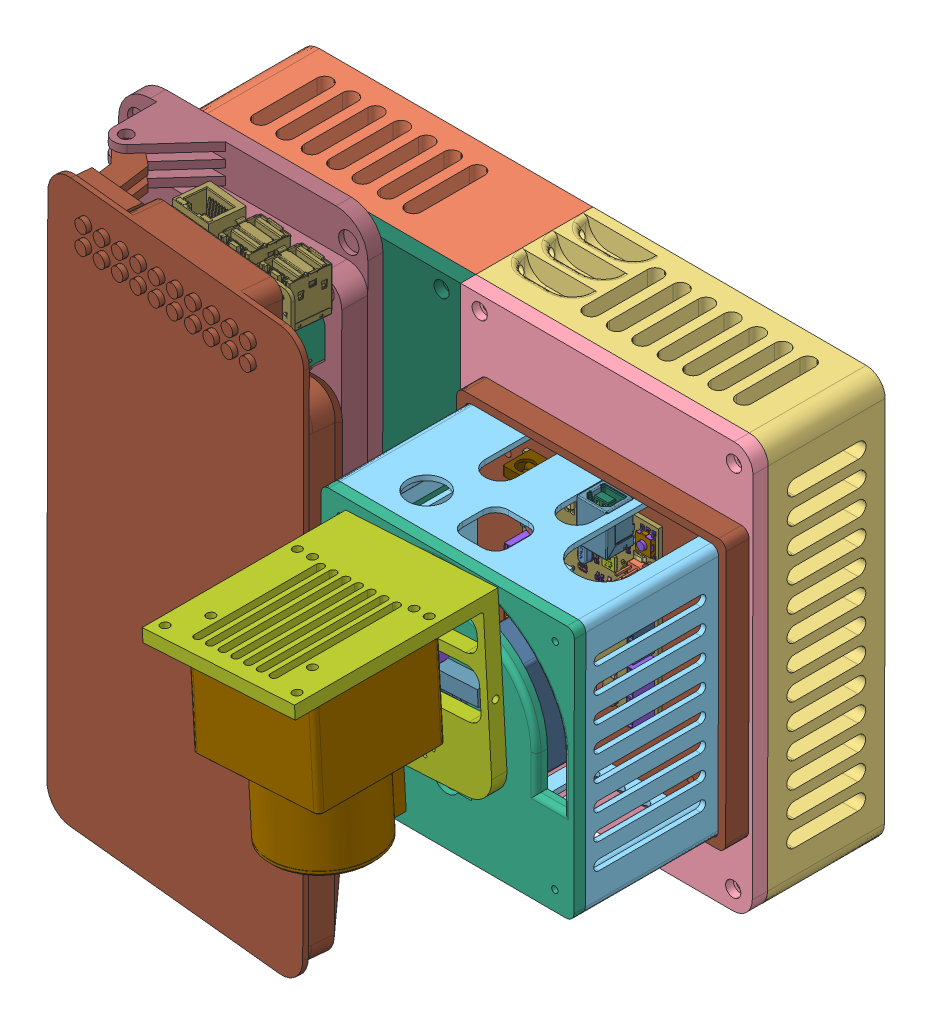
SolidWorks assembly Assembly, configuration Default. Lengths in mm.
Overall size (245.46 221.26 204).
103 component instances, 51 part files, 118 mates.
Components (placement in the parent):
- Battery-1: Battery [Default] at (165.4285 78.509 186.5432) x (0.999998 -0.001966 0) z (0 0 1) size (206 135 33)
- Battery Case_1-2: Battery Case_1 [Default] at (165.9287 78.6137 180.0432) x (0.999998 -0.001966 0) z (0 0 1) size (115.25 160.11 46)
- Battery Case_2-2: Battery Case_2 [Default] at (165.9287 78.6432 180.0432) x (0.999998 -0.001966 0) z (0 0 1) size (115.25 160.11 46)
- Top Plate-1: Top Plate [Default] at (165.9287 78.6432 226.0432) x (-0.999998 0.001966 0) z (0 0 1) size (115 160 6)
- Arduino Case Top_Final V2-1: Arduino Case Top_Final V2 [Default] at (226.1792 53.5753 296.0432) x (-0.00198 -0.999998 0) z (0 0 -1) size (99.6 99.6 55)
- Arduino Case Top Mg995_1Nm_play_top V2-2: Arduino Case Top Mg995_1Nm_play_top V2 [Default] at (226.1792 53.5753 296.0432) x (-0.00198 -0.999998 0) z (0 0 -1) size (99.6 99.6 9.5)
- Lidar L-Bracket_V2-1: Lidar L-Bracket_V2 [Default] at (253.0441 129.2768 384.0432) x (0 0 -1) z (0.998295 0.058377 0) size (80 70.73 60)
- 6mm Bearing SKF 626 (RS 286-7833)-1: 6mm Bearing SKF 626 (RS 286-7833) [Default] at (224.6698 100.5994 307.0432) x (0.058377 -0.998295 0) z (0.000041 0.000002 1) size (6 19 19)
- Lidar-1: Lidar [Default] at (248.0526 128.985 372.0432) x (-0.998295 -0.058377 0) z (0 0 1) size (50 70 50)
- TowerProMG995-1: TowerProMG995 [Default] at (226.1051 65.1996 276.0432) x (0.00198 0.999998 0) z (0.999998 -0.00198 0) size (55.5 43.5 20.7)
- Arduino Case Base V2-1: Arduino Case Base V2 [Default] at (227.3829 55.5376 232.0432) x (0.001973 0.999998 0) z (0.999998 -0.001973 0) size (106 10 106)
- User Library-arduino_uno-1: User Library-arduino_uno [Default] at (199.1691 122.679 240.6932) x (-0.999993 0.003694 0) z (0.003694 0.999993 0) size (53.34 15.25 74.93)
  - User Library-arduino_uno_unoboard blue-1: User Library-arduino_uno_unoboard blue [Default] at origin size (53.34 1.65 68.58)
  - User Library-arduino_uno_47uf CAP Dcase-1: User Library-arduino_uno_47uf CAP Dcase [Default] at (-9.4141 0 -18.4991) x (0 0 -1) z (1 0 0) size (6.6 5.81 8)
  - User Library-arduino_uno_USB SHELL-1: User Library-arduino_uno_USB SHELL [Default] at (-38.02 0.43 6.35) size (13.72 15.2 16.51)
  - User Library-arduino_uno_USB core-1: User Library-arduino_uno_USB core [Default] at (-38.02 0.43 6.35) size (11.3 10.68 15.75)
  - User Library-arduino_uno_usb top contact-1: User Library-arduino_uno_usb top contact [Default] at (-36.77 6.52 5.97) size (1 9.67 13.76)
  - User Library-arduino_uno_usb btm contact-1: User Library-arduino_uno_usb btm contact [Default] at (-36.77 4.84 5.97) size (1 6.84 11.76)
  - User Library-arduino_uno_usb btm contact-2: User Library-arduino_uno_usb btm contact [Default] at (-39.27 4.84 5.97) size (1 6.84 11.76)
  - User Library-arduino_uno_usb top contact-2: User Library-arduino_uno_usb top contact [Default] at (-39.27 6.52 5.97) size (1 9.67 13.76)
  - User Library-arduino_uno_power jack-1: User Library-arduino_uno_power jack [Default] at (-7.675 0 1.905) size (11.2 15.2 15.9)
  - User Library-arduino_uno_47uf CAP Dcase-2: User Library-arduino_uno_47uf CAP Dcase [Default] at (-9.4141 0 -25.7132) x (0 0 -1) z (1 0 0) size (6.6 5.81 8)
  - User Library-arduino_uno_crystal-1: User Library-arduino_uno_crystal [Default] at (-26.162 0 -18.923) x (1 0 0) z (0 0 -1) size (4 5 11)
  - User Library-arduino_uno_2pin_header__02-1: User Library-arduino_uno_2pin_header__02 [Default] at (-46.23 0 -15.75) size (5 11.75 2.54)
  - User Library-arduino_uno_nano - reg-1: User Library-arduino_uno_nano - reg [Default] at (-17.399 0 -7.747) size (6.5 1.69 8.3)
  - User Library-arduino_uno_led-1: User Library-arduino_uno_led [Default] at (-34.29 0 -27.94) x (0 0 1) z (-1 0 0) size (4 0.9 1.55)
  - User Library-arduino_uno_2pin_header__02-2: User Library-arduino_uno_2pin_header__02 [Default] at (-30.43 0 -64.91) x (0 0 1) z (-1 0 0) size (5 11.75 2.54)
  - User Library-arduino_uno_dip28-1: User Library-arduino_uno_dip28 [Default] at (-16.383 1.5 -46.355) x (0 0 -1) z (1 0 0) size (35.48 2.8 10.1)
  - User Library-arduino_uno_dip socket pin-1: User Library-arduino_uno_dip socket pin [Default] at (-20.193 4.3 -62.865) x (0 0 -1) z (1 0 0) size (1.7 7.37 1.7)
  - User Library-arduino_uno_dip socket pin-2: User Library-arduino_uno_dip socket pin [Default] at (-12.573 4.3 -62.865) x (0 0 -1) z (1 0 0) size (1.7 7.37 1.7)
  - User Library-arduino_uno_dip socket pin-3: User Library-arduino_uno_dip socket pin [Default] at (-20.193 4.3 -60.325) x (0 0 -1) z (1 0 0) size (1.7 7.37 1.7)
  - User Library-arduino_uno_dip socket pin-4: User Library-arduino_uno_dip socket pin [Default] at (-12.573 4.3 -60.325) x (0 0 -1) z (1 0 0) size (1.7 7.37 1.7)
  - User Library-arduino_uno_dip socket pin-5: User Library-arduino_uno_dip socket pin [Default] at (-20.193 4.3 -57.785) x (0 0 -1) z (1 0 0) size (1.7 7.37 1.7)
  - User Library-arduino_uno_dip socket pin-6: User Library-arduino_uno_dip socket pin [Default] at (-12.573 4.3 -57.785) x (0 0 -1) z (1 0 0) size (1.7 7.37 1.7)
  - User Library-arduino_uno_dip socket pin-7: User Library-arduino_uno_dip socket pin [Default] at (-20.193 4.3 -55.245) x (0 0 -1) z (1 0 0) size (1.7 7.37 1.7)
  - User Library-arduino_uno_dip socket pin-8: User Library-arduino_uno_dip socket pin [Default] at (-12.573 4.3 -55.245) x (0 0 -1) z (1 0 0) size (1.7 7.37 1.7)
  - User Library-arduino_uno_dip socket pin-9: User Library-arduino_uno_dip socket pin [Default] at (-20.193 4.3 -52.705) x (0 0 -1) z (1 0 0) size (1.7 7.37 1.7)
  - User Library-arduino_uno_dip socket pin-10: User Library-arduino_uno_dip socket pin [Default] at (-12.573 4.3 -52.705) x (0 0 -1) z (1 0 0) size (1.7 7.37 1.7)
  - User Library-arduino_uno_dip socket pin-11: User Library-arduino_uno_dip socket pin [Default] at (-20.193 4.3 -50.165) x (0 0 -1) z (1 0 0) size (1.7 7.37 1.7)
  - User Library-arduino_uno_dip socket pin-12: User Library-arduino_uno_dip socket pin [Default] at (-12.573 4.3 -50.165) x (0 0 -1) z (1 0 0) size (1.7 7.37 1.7)
  - User Library-arduino_uno_dip socket pin-13: User Library-arduino_uno_dip socket pin [Default] at (-20.193 4.3 -47.625) x (0 0 -1) z (1 0 0) size (1.7 7.37 1.7)
  - User Library-arduino_uno_dip socket pin-14: User Library-arduino_uno_dip socket pin [Default] at (-12.573 4.3 -47.625) x (0 0 -1) z (1 0 0) size (1.7 7.37 1.7)
  - User Library-arduino_uno_dip socket pin-15: User Library-arduino_uno_dip socket pin [Default] at (-20.193 4.3 -45.085) x (0 0 -1) z (1 0 0) size (1.7 7.37 1.7)
  - User Library-arduino_uno_dip socket pin-16: User Library-arduino_uno_dip socket pin [Default] at (-12.573 4.3 -45.085) x (0 0 -1) z (1 0 0) size (1.7 7.37 1.7)
  - User Library-arduino_uno_dip socket pin-17: User Library-arduino_uno_dip socket pin [Default] at (-20.193 4.3 -42.545) x (0 0 -1) z (1 0 0) size (1.7 7.37 1.7)
  - User Library-arduino_uno_dip socket pin-18: User Library-arduino_uno_dip socket pin [Default] at (-12.573 4.3 -42.545) x (0 0 -1) z (1 0 0) size (1.7 7.37 1.7)
  - User Library-arduino_uno_dip socket pin-19: User Library-arduino_uno_dip socket pin [Default] at (-20.193 4.3 -40.005) x (0 0 -1) z (1 0 0) size (1.7 7.37 1.7)
  - User Library-arduino_uno_dip socket pin-20: User Library-arduino_uno_dip socket pin [Default] at (-12.573 4.3 -40.005) x (0 0 -1) z (1 0 0) size (1.7 7.37 1.7)
  - User Library-arduino_uno_dip socket pin-21: User Library-arduino_uno_dip socket pin [Default] at (-20.193 4.3 -37.465) x (0 0 -1) z (1 0 0) size (1.7 7.37 1.7)
  - User Library-arduino_uno_dip socket pin-22: User Library-arduino_uno_dip socket pin [Default] at (-12.573 4.3 -37.465) x (0 0 -1) z (1 0 0) size (1.7 7.37 1.7)
  - User Library-arduino_uno_dip socket pin-23: User Library-arduino_uno_dip socket pin [Default] at (-20.193 4.3 -34.925) x (0 0 -1) z (1 0 0) size (1.7 7.37 1.7)
  - User Library-arduino_uno_dip socket pin-24: User Library-arduino_uno_dip socket pin [Default] at (-12.573 4.3 -34.925) x (0 0 -1) z (1 0 0) size (1.7 7.37 1.7)
  - User Library-arduino_uno_dip socket pin-25: User Library-arduino_uno_dip socket pin [Default] at (-20.193 4.3 -32.385) x (0 0 -1) z (1 0 0) size (1.7 7.37 1.7)
  - User Library-arduino_uno_dip socket pin-26: User Library-arduino_uno_dip socket pin [Default] at (-12.573 4.3 -32.385) x (0 0 -1) z (1 0 0) size (1.7 7.37 1.7)
  - User Library-arduino_uno_dip socket pin-27: User Library-arduino_uno_dip socket pin [Default] at (-20.193 4.3 -29.845) x (0 0 -1) z (1 0 0) size (1.7 7.37 1.7)
  - User Library-arduino_uno_dip socket pin-28: User Library-arduino_uno_dip socket pin [Default] at (-12.573 4.3 -29.845) x (0 0 -1) z (1 0 0) size (1.7 7.37 1.7)
  - User Library-arduino_uno_2pin_header__02-3: User Library-arduino_uno_2pin_header__02 [Default] at (-27.89 0 -64.91) x (0 0 1) z (-1 0 0) size (5 11.75 2.54)
  - User Library-arduino_uno_2pin_header__02-4: User Library-arduino_uno_2pin_header__02 [Default] at (-25.35 0 -64.91) x (0 0 1) z (-1 0 0) size (5 11.75 2.54)
  - User Library-arduino_uno_2pin_header__02-5: User Library-arduino_uno_2pin_header__02 [Default] at (-46.23 0 -18.29) size (5 11.75 2.54)
  - User Library-arduino_uno_2pin_header__02-6: User Library-arduino_uno_2pin_header__02 [Default] at (-46.23 0 -20.83) size (5 11.75 2.54)
  - User Library-arduino_uno_atmega16u2-1: User Library-arduino_uno_atmega16u2 [Default] at (-34.671 0.06 -20) x (1 0 0) z (0 0 -1) size (5.5 1.01 5.5)
  - User Library-arduino_uno_led-2: User Library-arduino_uno_led [Default] at (-36.83 0 -27.94) x (0 0 1) z (-1 0 0) size (4 0.9 1.55)
  - User Library-arduino_uno_led-3: User Library-arduino_uno_led [Default] at (-42.037 0 -27.94) x (0 0 1) z (-1 0 0) size (4 0.9 1.55)
  - User Library-arduino_uno_led-4: User Library-arduino_uno_led [Default] at (-36.576 0 -58.42) x (0 0 1) z (-1 0 0) size (4 0.9 1.55)
  - User Library-arduino_uno_8 PORT HEADER-1: User Library-arduino_uno_8 PORT HEADER [Default] at (-50.8 0 -45.72) x (0 0 -1) z (1 0 0) size (20.32 10.51 2.41)
  - User Library-arduino_uno_8 PORT HEADER-2: User Library-arduino_uno_8 PORT HEADER [Default] at (-2.54 0 -27.94) x (0 0 -1) z (1 0 0) size (20.32 10.51 2.41)
  - User Library-arduino_uno_6 PORT HEADER-1: User Library-arduino_uno_6 PORT HEADER [Default] at (-2.54 0 -50.8) x (0 0 -1) z (1 0 0) size (15.24 10.51 2.41)
  - User Library-arduino_uno_10 PORT HEADER-1: User Library-arduino_uno_10 PORT HEADER [Default] at (-50.8 0 -18.796) x (0 0 -1) z (1 0 0) size (25.4 10.51 2.41)
  - User Library-arduino_uno_ATMEL328P-1: User Library-arduino_uno_ATMEL328P [Default] at (-16.383 4.3 -46.355) x (0 0 -1) z (1 0 0) size (35 7.27 7.87)
  - User Library-arduino_uno_102 RESISTOR PACK-1: User Library-arduino_uno_102 RESISTOR PACK [Default] at (-33.782 0 -58.42) size (3.2 0.51 3)
  - User Library-arduino_uno_102 RESISTOR PACK-2: User Library-arduino_uno_102 RESISTOR PACK [Default] at (-39.37 0 -27.94) size (3.2 0.51 3)
  - User Library-arduino_uno_103 RESISTOR PACK-1: User Library-arduino_uno_103 RESISTOR PACK [Default] at (-23.876 0 -27.94) size (3.2 0.51 3)
  - User Library-arduino_uno_220 RESISTOR PACK-1: User Library-arduino_uno_220 RESISTOR PACK [Default] at (-36.83 0 -12.827) size (3.2 0.51 3)
  - User Library-arduino_uno_16mhz crystal - measured-1: User Library-arduino_uno_16mhz crystal - measured [Default] at (-24.892 0 -41.275) x (0 0 -1) z (1 0 0) size (3.4 0.8 2)
  - User Library-arduino_uno_PADS001-1: User Library-arduino_uno_PADS001 [Default] at (-39.878 0.1 -18.288) x (-1 0 0) z (0 0 1) size (4.54 0.1 4.54)
  - User Library-arduino_uno_603 cap on pad-1: User Library-arduino_uno_603 cap on pad [Default] at (-44.45 0 -27.94) x (0 0 -1) z (1 0 0) size (2.76 0.91 1.02)
  - User Library-arduino_uno_ssot3-1: User Library-arduino_uno_ssot3 [Default] at (-26.5 0 -8.128) x (-1 0 0) z (0 0 -1) size (3 1.13 3.09)
  - User Library-arduino_uno_603 cap on pad-2: User Library-arduino_uno_603 cap on pad [Default] at (-29.845 0 -27.94) x (0 0 -1) z (1 0 0) size (2.76 0.91 1.02)
  - User Library-arduino_uno_603 cap on pad-3: User Library-arduino_uno_603 cap on pad [Default] at (-31.496 0 -27.94) x (0 0 -1) z (1 0 0) size (2.76 0.91 1.02)
  - User Library-arduino_uno_lmv358-1: User Library-arduino_uno_lmv358 [Default] at (-15.24 0 -21.971) x (0 0 -1) z (1 0 0) size (3.7 1.4 2.9)
  - User Library-arduino_uno_603 cap on pad-4: User Library-arduino_uno_603 cap on pad [Default] at (-15.24 0 -18.415) size (2.76 0.91 1.02)
  - User Library-arduino_uno_603 cap on pad-5: User Library-arduino_uno_603 cap on pad [Default] at (-29.845 0 -12.065) x (0 0 1) z (-1 0 0) size (2.76 0.91 1.02)
  - User Library-arduino_uno_603 cap on pad-6: User Library-arduino_uno_603 cap on pad [Default] at (-29.591 0 -22.352) x (0 0 1) z (-1 0 0) size (2.76 0.91 1.02)
  - User Library-arduino_uno_603 cap on pad-7: User Library-arduino_uno_603 cap on pad [Default] at (-29.591 0 -16.002) x (0 0 1) z (-1 0 0) size (2.76 0.91 1.02)
  - User Library-arduino_uno_603 cap on pad-8: User Library-arduino_uno_603 cap on pad [Default] at (-41.91 0 -12.7) x (0 0 1) z (-1 0 0) size (2.76 0.91 1.02)
  - User Library-arduino_uno_lp2985dgkr-1: User Library-arduino_uno_lp2985dgkr [Default] at (-20.32 0 -19.05) x (0 0 -1) z (1 0 0) size (5.85 1.1 3)
  - User Library-arduino_uno_cd1206 diode-1: User Library-arduino_uno_cd1206 diode [Default] at (-27.94 0 -59.436) x (0 0 -1) z (1 0 0) size (2.09 0.96 5)
  - User Library-arduino_uno_cd1206 diode-2: User Library-arduino_uno_cd1206 diode [Default] at (-46.228 0 -13.081) x (0 0 1) z (-1 0 0) size (2.09 0.96 5)
  - User Library-arduino_uno_603 resistor-1: User Library-arduino_uno_603 resistor [Default] at (-29.591 0 -19.05) x (0 0 1) z (-1 0 0) size (2.36 0.62 1.03)
  - User Library-arduino_uno_blm21-1: User Library-arduino_uno_blm21 [Default] at (-45.085 0 -7.62) x (0 0 -1) z (1 0 0) size (2.78 0.95 1.32)
  - User Library-arduino_uno_m7 diode-1: User Library-arduino_uno_m7 diode [Default] at (-2.794 0 -21.59) x (0 0 -1) z (1 0 0) size (6.66 2.35 2.5)
  - User Library-arduino_uno_MLC0603-1: User Library-arduino_uno_MLC0603 [Default] at (-33.655 0 -12.827) x (0 0 -1) z (1 0 0) size (2.36 0.6 1.03)
  - User Library-arduino_uno_MLC0603-2: User Library-arduino_uno_MLC0603 [Default] at (-39.37 0 -12.827) x (0 0 -1) z (1 0 0) size (2.36 0.6 1.03)
  - User Library-arduino_uno_RESET CORE-1: User Library-arduino_uno_RESET CORE [Default] at (-49.403 0.1 -6.35) x (-1 0 0) z (0 0 -1) size (6.2 3.1 9.6)
  - User Library-arduino_uno_RESET-1: User Library-arduino_uno_RESET [Default] at (-49.403 0.1 -6.35) x (0 0 1) z (-1 0 0) size (7.3 2 6.2)
- Shuriken-1: Shuriken [Default] at (210.9142 94.658 284.324) x (0.998295 0.058377 0) z (0.058375 -0.998257 -0.008727) size (20 6.67 20.06)
  - ShurikenStarO V2-1: ShurikenStarO V2 [Default] at (14.079 19.8913 19.6413) x (1 0 0) z (0 -0.999962 0.008727) size (20 20 6.5)
- Pi Screen Assembly-1: Pi Screen Assembly [Default] at (218.9608 108.3082 200.5923) x (-0.001966 -0.999998 0) z (-0.999655 0.001965 -0.026177) size (221 61.76 131.08)
  - Pi Touch Screen-1: Pi Touch Screen [Default] at (61.75 84.4571 107.2044) x (1 0 0) z (0 0.997511 0.070505) size (221 114.52 33.01)
  - User Library-Raspberry Pi 3-2-1: User Library-Raspberry Pi 3-2 [Default] at (-18.5338 72.6927 106.2834) x (-1 0 0) z (0 -0.997511 -0.070505) size (89.64 57.31 18.59)
  - Raspberry Pi case-1: Raspberry Pi case [Default] at (29.5 34.9078 131.6046) x (1 0 0) z (0 0.999657 -0.026177) size (175 98 28)
- TBar v2-1: TBar v2 [Default] at (199.0993 92.495 310.0432) x (0.998295 0.058377 0) z (0 0 1) size (52 18 6)
- Top Plate V4-1: Top Plate V4 [Default] at (165.9286 78.6137 226.0432) x (-0.999998 0.001966 0) z (0 0 1) size (115 160 6)
Mates (geometry in assembly coordinates):
- Coincident32: coincident anti-aligned: plane of Battery-1 through (165.4285 78.509 186.5432) normal (0 0 -1); plane of Battery Case_1-2 through (165.9287 78.6137 186.5432) normal (0 0 1)
- Coincident34: coincident anti-aligned: plane of Battery-1 through (62.5614 146.2114 219.5432) normal (-0.999998 0.001966 0); plane of Battery Case_1-2 through (62.5862 158.8171 226.0432) normal (0.999998 -0.001966 0)
- Concentric28: concentric aligned: cylinder of Battery Case_1-2 through (158.5747 152.8783 193.0432) axis (0 0 -1) radius 1.375; cylinder of ? through (158.5747 152.8783 180.0432) axis (0 0 -1) radius 3.5
- Coincident35: coincident anti-aligned: plane of Battery Case_2-2 through (165.9287 78.6432 185.0432) normal (0 0 -1); plane of ? through (166.0747 152.8783 185.0432) normal (0 0 1)
- Concentric30: concentric aligned: cylinder of Battery Case_1-2 through (158.5747 152.8783 213.5432) axis (0 0 1) radius 1.375; cylinder of ? through (158.5747 152.8783 226.0432) axis (0 0 1) radius 1.7
- Coincident36: coincident anti-aligned: plane of Battery Case_2-2 through (165.9287 78.6432 221.0432) normal (0 0 1); plane of ? through (166.0747 152.8783 221.0432) normal (0 0 -1)
- Concentric31: concentric aligned: cylinder of Battery Case_1-2 through (158.2827 4.3786 213.5432) axis (0 0 1) radius 1.375; cylinder of ? through (158.2827 4.3786 226.0432) axis (0 0 1) radius 1.7
- Coincident37: coincident anti-aligned: plane of Battery Case_1-2 through (165.9287 78.6137 221.0432) normal (0 0 1); plane of ? through (165.7827 4.3786 221.0432) normal (0 0 -1)
- Concentric33: concentric aligned: cylinder of Battery Case_1-2 through (158.2827 4.3786 193.0432) axis (0 0 -1) radius 1.375; cylinder of ? through (158.2827 4.3786 180.0432) axis (0 0 -1) radius 3.5
- Concentric34: concentric aligned: cylinder of Battery Case_2-2 through (173.2827 4.3786 193.0432) axis (0 0 -1) radius 1.375; cylinder of ? through (173.2827 4.3786 180.0432) axis (0 0 -1) radius 3.5
- Coincident38: coincident anti-aligned: plane of Battery Case_2-2 through (165.9287 78.6432 185.0432) normal (0 0 -1); plane of ? through (165.7827 4.3786 185.0432) normal (0 0 1)
- Concentric35: concentric aligned: cylinder of Battery Case_1-2 through (158.5747 152.8783 213.0432) axis (0 0 1) radius 1.375; cone of ? through (158.5747 152.8783 215.1468) axis (0 0 1)
- Concentric36: concentric anti-aligned: cylinder of Battery Case_2-2 through (173.5747 152.8783 213.0432) axis (0 0 1) radius 1.375; cone of ? through (173.5747 152.8783 218.8432) axis (0 0 -1)
- Coincident41: coincident: cylinder of Battery Case_1-2 through (158.2827 4.3786 213.0432) axis (0 0 1) radius 1.375; circle of ?
- Coincident43: coincident: cylinder of Battery Case_2-2 through (173.2827 4.3786 213.0432) axis (0 0 1) radius 1.375; circle of ?
- Coincident45: coincident: cylinder of Battery Case_2-2 through (173.5747 152.8783 193.0432) axis (0 0 -1) radius 1.375; circle of ?
- Concentric37: concentric aligned: cylinder of Battery Case_1-2 through (158.5747 152.8783 193.0432) axis (0 0 -1) radius 1.375; cone of ? through (158.5747 152.8783 188.9396) axis (0 0 -1)
- Concentric38: concentric aligned: cylinder of Lidar L-Bracket_V2-1 through (238.5582 106.957 304.0432) axis (-0.875243 -0.483683 0) radius 1.35; cylinder of ? through (204.4237 88.0933 304.0432) axis (-0.875243 -0.483683 0) radius 1.25
- Concentric39: concentric anti-aligned: cylinder of Lidar L-Bracket_V2-1 through (206.3227 111.5341 304.0432) axis (0.483683 -0.875243 0) radius 1.35; cylinder of ? through (214.5443 96.6568 304.0432) axis (-0.483683 0.875243 0) radius 1.25
- Concentric40: concentric anti-aligned: cylinder of Lidar L-Bracket_V2-1 through (238.5582 106.957 304.0432) axis (-0.875243 -0.483683 0) radius 1.35; cylinder of ? through (227.1801 100.6691 304.0432) axis (0.875243 0.483683 0) radius 1.25
- Concentric41: concentric aligned: cylinder of ? through (211.1585 102.7835 304.0432) axis (0.483683 -0.875243 0) radius 2.93; cylinder of 6mm Bearing SKF 626 (RS 286-7833)-1 through (214.0617 97.5302 304.0432) axis (0.483683 -0.875243 0) radius 3
- Coincident52: coincident anti-aligned: plane of Lidar L-Bracket_V2-1 through (254.2684 108.3405 300.0432) normal (0.058377 -0.998295 0); plane of 6mm Bearing SKF 626 (RS 286-7833)-1 through (224.3196 106.5892 307.0432) normal (-0.058377 0.998295 0)
- Concentric43: concentric anti-aligned: cylinder of Arduino Case Base V2-1 through (234.4849 56.508 238.0432) axis (0 0 -1) radius 1.5; cylinder of User Library-arduino_uno-1/User Library-arduino_uno_unoboard blue-1 through (234.4849 56.508 239.0432) axis (0 0 1) radius 1.5875
- Parallel1: parallel anti-aligned: cylinder of Arduino Case Base V2-1 through (206.3849 56.5635 238.0432) axis (0 0 -1) radius 1.5; cylinder of User Library-arduino_uno-1/User Library-arduino_uno_unoboard blue-1 through (206.5451 56.6113 239.0432) axis (0 0 1) radius 1.5875
- Lock1: lock: unknown of Arduino Case Base V2-1; unknown of ?
- Concentric45: concentric anti-aligned: cylinder of Lidar L-Bracket_V2-1 through (242.7693 133.6846 367.0432) axis (0.058377 -0.998295 0) radius 1.7; cylinder of Lidar-1 through (245.3962 88.7613 367.0432) axis (-0.058377 0.998295 0) radius 1.5
- Concentric46: concentric anti-aligned: cylinder of Lidar L-Bracket_V2-1 through (202.8375 131.3495 327.0432) axis (0.058377 -0.998295 0) radius 1.7; cylinder of Lidar-1 through (205.4645 86.4262 327.0432) axis (-0.058377 0.998295 0) radius 1.5
- Coincident54: coincident anti-aligned: plane of Lidar L-Bracket_V2-1 through (253.0441 129.2768 384.0432) normal (0.058377 -0.998295 0); plane of Lidar-1 through (248.0526 128.985 372.0432) normal (-0.058377 0.998295 0)
- Concentric52: concentric aligned: cylinder of Battery Case_2-2 through (273.2859 5.932 216.0432) axis (0 0 1) radius 1.375; cylinder of Top Plate-1 through (273.2859 5.932 222.0432) axis (0 0 1) radius 1.75
- Concentric56: concentric aligned: cylinder of Battery Case_2-2 through (273.571 150.9317 216.0432) axis (0 0 1) radius 1.375; cylinder of Top Plate-1 through (273.571 150.9317 222.0432) axis (0 0 1) radius 1.75
- Parallel5: parallel aligned: cylinder of Battery Case_1-2 through (58.2863 6.3252 216.0432) axis (0 0 1) radius 1.375; cylinder of Top Plate-1 through (58.2864 6.3547 222.0432) axis (0 0 1) radius 1.75
- Coincident56: coincident anti-aligned: plane of Battery Case_1-2 through (165.9287 78.6137 226.0432) normal (0 0 1); plane of Top Plate-1 through (273.571 150.9317 226.0432) normal (0 0 -1)
- Concentric60: concentric aligned: cylinder of Battery Case_1-2 through (58.5714 151.3249 216.0432) axis (0 0 1) radius 1.375; cone of ? through (58.5714 151.3249 222.8468) axis (0 0 1)
- Coincident62: coincident anti-aligned: plane of Top Plate-1 through (58.5714 151.3544 228.5432) normal (0 0 1); plane of ? through (58.5714 154.0749 228.5432) normal (0 0 -1)
- Coincident63: coincident: cylinder of Battery Case_2-2 through (273.571 150.9317 216.0432) axis (0 0 1) radius 1.375; circle of ?
- Coincident64: coincident anti-aligned: plane of Top Plate-1 through (273.571 150.9317 228.5432) normal (0 0 1); plane of ? through (273.571 153.6817 228.5432) normal (0 0 -1)
- Coincident65: coincident: cylinder of Battery Case_1-2 through (58.2863 6.3252 216.0432) axis (0 0 1) radius 1.375; circle of ?
- Coincident66: coincident anti-aligned: plane of Top Plate-1 through (58.2864 6.3547 228.5432) normal (0 0 1); plane of ? through (58.2863 9.0752 228.5432) normal (0 0 -1)
- Coincident67: coincident: cylinder of Battery Case_2-2 through (273.2859 5.932 216.0432) axis (0 0 1) radius 1.375; circle of ?
- Coincident68: coincident anti-aligned: plane of Top Plate-1 through (273.2859 5.932 228.5432) normal (0 0 1); plane of ? through (273.2859 8.682 228.5432) normal (0 0 -1)
- Coincident69: coincident anti-aligned: plane of Arduino Case Top_Final V2-1 through (226.1792 53.5753 293.0432) normal (0 0 1); plane of Arduino Case Top Mg995_1Nm_play_top V2-2 through (226.1792 53.5753 293.0432) normal (0 0 -1)
- Coincident70: coincident anti-aligned: plane of Arduino Case Top Mg995_1Nm_play_top V2-2 through (226.1792 53.5753 294.5432) normal (0 0 1); plane of ? through (184.0449 39.0587 294.5432) normal (0 0 -1)
- Coincident71: coincident anti-aligned: plane of Arduino Case Top Mg995_1Nm_play_top V2-2 through (226.1792 53.5753 294.5432) normal (0 0 1); plane of ? through (268.6447 38.8912 294.5432) normal (0 0 -1)
- Coincident72: coincident anti-aligned: plane of Arduino Case Top Mg995_1Nm_play_top V2-2 through (226.1792 53.5753 294.5432) normal (0 0 1); plane of ? through (268.8123 123.491 294.5432) normal (0 0 -1)
- Coincident73: coincident anti-aligned: plane of Arduino Case Top Mg995_1Nm_play_top V2-2 through (226.1792 53.5753 294.5432) normal (0 0 1); plane of ? through (184.2124 123.6585 294.5432) normal (0 0 -1)
- Concentric711: concentric aligned: cylinder of User Library-arduino_uno-1/User Library-arduino_uno_unoboard blue-1 through (206.5451 56.6113 239.0432) axis (0 0 1) radius 1.5875; cylinder of ? through (206.5451 56.6113 275.4432) axis (0 0 1) radius 2.75
- Coincident781: coincident anti-aligned: plane of User Library-arduino_uno-1/User Library-arduino_uno_unoboard blue-1 through (252.5087 122.4819 240.6932) normal (0 0 1); plane of ? through (206.5451 59.3613 240.6932) normal (0 0 -1)
- Concentric721: concentric aligned: cylinder of User Library-arduino_uno-1/User Library-arduino_uno_unoboard blue-1 through (234.4849 56.508 239.0432) axis (0 0 1) radius 1.5875; cylinder of ? through (234.4849 56.508 275.4432) axis (0 0 1) radius 2.75
- Coincident791: coincident anti-aligned: plane of User Library-arduino_uno-1/User Library-arduino_uno_unoboard blue-1 through (252.5087 122.4819 240.6932) normal (0 0 1); plane of ? through (234.4849 59.258 240.6932) normal (0 0 -1)
- Concentric731: concentric aligned: cylinder of User Library-arduino_uno-1/User Library-arduino_uno_unoboard blue-1 through (201.6575 108.6997 239.0432) axis (0 0 1) radius 1.5875; cylinder of ? through (201.6575 108.6997 275.4432) axis (0 0 1) radius 2.75
- Coincident801: coincident anti-aligned: plane of User Library-arduino_uno-1/User Library-arduino_uno_unoboard blue-1 through (252.5087 122.4819 240.6932) normal (0 0 1); plane of ? through (201.6575 111.4497 240.6932) normal (0 0 -1)
- Concentric741: concentric aligned: cylinder of User Library-arduino_uno-1/User Library-arduino_uno_unoboard blue-1 through (249.9124 107.2514 239.0432) axis (0 0 1) radius 1.5875; cylinder of ? through (249.9124 107.2514 275.4432) axis (0 0 1) radius 2.75
- Coincident811: coincident anti-aligned: plane of User Library-arduino_uno-1/User Library-arduino_uno_unoboard blue-1 through (252.5087 122.4819 240.6932) normal (0 0 1); plane of ? through (249.9124 110.0014 240.6932) normal (0 0 -1)
- Parallel7: parallel aligned: cylinder of Arduino Case Top Mg995_1Nm_play_top V2-2 through (231.1526 89.1896 288.0432) axis (0 0 1) radius 1.375; cylinder of TowerProMG995-1 through (221.0576 41.2095 258.0422) axis (0 0 1) radius 1.75
- Concentric749: concentric aligned: cylinder of Arduino Case Top Mg995_1Nm_play_top V2-2 through (231.0576 41.1897 288.0432) axis (0 0 1) radius 1.375; cylinder of TowerProMG995-1 through (231.0576 41.1897 258.0422) axis (0 0 1) radius 1.75
- Concentric751: concentric aligned: cylinder of Arduino Case Top Mg995_1Nm_play_top V2-2 through (231.1526 89.1896 288.0432) axis (0 0 1) radius 1.375; cylinder of TowerProMG995-1 through (231.1526 89.1896 258.0422) axis (0 0 1) radius 1.75
- Concentric753: concentric anti-aligned: cylinder of TowerProMG995-1 through (226.1259 75.6995 298.5432) axis (0 0 -1) radius 2.5; cylinder of Shuriken-1/ShurikenStarO V2-1 through (226.1259 75.6995 297.5432) axis (0 0 1) radius 3
- Coincident850: coincident anti-aligned: plane of TowerProMG995-1 through (226.1259 75.6995 301.5432) normal (0 0 1); plane of Shuriken-1/ShurikenStarO V2-1 through (226.1259 75.6995 301.5432) normal (0 0 -1)
- Coincident851: coincident anti-aligned: plane of Arduino Case Top Mg995_1Nm_play_top V2-2 through (221.2497 89.2092 288.0432) normal (0 0 -1); plane of TowerProMG995-1 through (215.8962 85.9698 288.0432) normal (0 0 1)
- Concentric754: concentric anti-aligned: cylinder of ? through (229.2113 82.8919 295.0432) axis (0 0 1) radius 0.75; cylinder of ? through (229.2113 82.8919 299.4432) axis (0 0 -1) radius 0.75
- Concentric755: concentric anti-aligned: cylinder of ? through (233.3183 72.6141 295.0432) axis (0 0 1) radius 0.75; cylinder of ? through (233.3183 72.6141 299.4432) axis (0 0 -1) radius 0.75
- Coincident852: coincident anti-aligned: plane of ? through (226.1259 75.6995 301.0432) normal (0 0 1); plane of ? through (226.1259 75.6995 301.0432) normal (0 0 -1)
- Tangent2: tangent anti-aligned: plane of Arduino Case Top Mg995_1Nm_play_top V2-2 through (226.1792 53.5753 297.5432) normal (0 0 1); cylinder of 6mm Bearing SKF 626 (RS 286-7833)-1 through (224.6698 100.5994 307.0432) axis (0.058377 -0.998295 0) radius 9.5
- Coincident8625: coincident anti-aligned: plane of Top Plate-1 through (273.571 150.9317 232.0432) normal (0 0 1); plane of Pi Screen Assembly-1/Raspberry Pi case-1 through (50.0773 154.1404 232.0432) normal (0 0 -1)
- Parallel15: parallel aligned: plane of Battery Case_1-2 through (50.7716 -1.16 226.0432) normal (-0.001966 -0.999998 0); plane of Pi Screen Assembly-1/Raspberry Pi case-1 through (49.7578 -8.3593 238.0432) normal (-0.001966 -0.999998 0)
- Concentric7599: concentric aligned: cylinder of Top Plate-1 through (268.6453 36.1412 226.0432) axis (0 0 1) radius 1.5; cylinder of Arduino Case Base V2-1 through (268.6447 36.1418 228.0432) axis (0 0 1) radius 1.5
- Concentric7600: concentric aligned: cylinder of Top Plate-1 through (184.2118 120.9074 226.0432) axis (0 0 1) radius 1.5; cylinder of Arduino Case Base V2-1 through (184.2118 120.9074 228.0432) axis (0 0 1) radius 1.5
- Coincident8629: coincident anti-aligned: plane of Top Plate-1 through (273.571 150.9317 232.0432) normal (0 0 1); plane of Arduino Case Base V2-1 through (227.3829 55.5376 232.0432) normal (0 0 -1)
- Concentric7601: concentric anti-aligned: cylinder of Arduino Case Top_Final V2-1 through (268.8123 120.741 248.0432) axis (0 0 -1) radius 1.375; cylinder of Arduino Case Base V2-1 through (268.8117 120.7404 228.0432) axis (0 0 1) radius 1.5
- Concentric7602: concentric anti-aligned: cylinder of Arduino Case Top_Final V2-1 through (184.0449 36.3087 248.0432) axis (0 0 -1) radius 1.375; cylinder of Arduino Case Base V2-1 through (184.0449 36.3087 228.0432) axis (0 0 1) radius 1.5
- Coincident8630: coincident anti-aligned: plane of Arduino Case Top_Final V2-1 through (226.1792 53.5753 238.0432) normal (0 0 -1); plane of Arduino Case Base V2-1 through (227.3829 55.5376 238.0432) normal (0 0 1)
- Concentric76031: concentric anti-aligned: cylinder of Lidar L-Bracket_V2-1 through (242.7693 133.6846 324.0432) axis (0.058377 -0.998295 0) radius 1.7; cylinder of ? through (240.7407 168.3753 324.0432) axis (-0.058377 0.998295 0) radius 2.75
- Coincident86321: coincident anti-aligned: plane of Lidar L-Bracket_V2-1 through (252.7522 134.2683 381.0432) normal (-0.058377 0.998295 0); plane of ? through (242.7358 133.6826 321.2934) normal (0.058377 -0.998295 0)
- Concentric76041: concentric anti-aligned: cylinder of Lidar L-Bracket_V2-1 through (202.8375 131.3495 324.0432) axis (0.058377 -0.998295 0) radius 1.7; cylinder of ? through (200.8089 166.0402 324.0432) axis (-0.058377 0.998295 0) radius 2.75
- Coincident86331: coincident anti-aligned: plane of Lidar L-Bracket_V2-1 through (252.7522 134.2683 381.0432) normal (-0.058377 0.998295 0); plane of ? through (202.804 131.3475 321.2934) normal (0.058377 -0.998295 0)
- Concentric76051: concentric anti-aligned: cylinder of Lidar L-Bracket_V2-1 through (242.7693 133.6846 364.0432) axis (0.058377 -0.998295 0) radius 1.7; cylinder of ? through (240.7407 168.3753 364.0432) axis (-0.058377 0.998295 0) radius 2.75
- Coincident86341: coincident anti-aligned: plane of Lidar L-Bracket_V2-1 through (252.7522 134.2683 381.0432) normal (-0.058377 0.998295 0); plane of ? through (242.7358 133.6826 361.2934) normal (0.058377 -0.998295 0)
- Concentric76061: concentric anti-aligned: cylinder of Lidar L-Bracket_V2-1 through (202.8375 131.3495 364.0432) axis (0.058377 -0.998295 0) radius 1.7; cylinder of ? through (200.8089 166.0402 364.0432) axis (-0.058377 0.998295 0) radius 2.75
- Coincident86351: coincident anti-aligned: plane of Lidar L-Bracket_V2-1 through (252.7522 134.2683 381.0432) normal (-0.058377 0.998295 0); plane of ? through (202.804 131.3475 361.2934) normal (0.058377 -0.998295 0)
- Concentric76071: concentric anti-aligned: cylinder of Lidar L-Bracket_V2-1 through (254.8287 98.759 304.0432) axis (-0.998295 -0.058377 0) radius 1.35; cylinder of ? through (289.5194 100.7876 304.0432) axis (0.998295 0.058377 0) radius 2.75
- Coincident86361: coincident anti-aligned: plane of Lidar L-Bracket_V2-1 through (252.7522 134.2683 381.0432) normal (0.998295 0.058377 0); plane of ? through (254.7647 99.8538 301.5214) normal (-0.998295 -0.058377 0)
- Concentric76081: concentric anti-aligned: cylinder of Lidar L-Bracket_V2-1 through (206.3227 111.5341 304.0432) axis (0.483683 -0.875243 0) radius 1.35; cylinder of ? through (192.4168 136.6973 304.0432) axis (-0.483683 0.875243 0) radius 2.75
- Coincident86371: coincident anti-aligned: plane of Lidar L-Bracket_V2-1; plane of ? through (209.1955 106.2664 301.2934) normal (0.483683 -0.875243 0)
- Concentric76091: concentric aligned: cylinder of Lidar L-Bracket_V2-1 through (254.8287 98.759 304.0432) axis (-0.998295 -0.058377 0) radius 1.35; cylinder of ? through (160.2403 93.2278 304.0432) axis (-0.998295 -0.058377 0) radius 2.75
- Coincident86381: coincident anti-aligned: plane of Lidar L-Bracket_V2-1 through (192.8545 130.7657 381.0432) normal (-0.998295 -0.058377 0); plane of ? through (194.884 96.0596 306.6729) normal (0.998295 0.058377 0)
- Concentric7610: concentric aligned: cylinder of ? through (57.5293 151.3577 255.0432) axis (0.001966 0.999998 0) radius 2.5; cylinder of ? through (57.5642 169.1077 255.0432) axis (0.001966 0.999998 0) radius 4.75
- Coincident8639: coincident anti-aligned: plane of ? through (50.1022 166.3724 238.0432) normal (0.001966 0.999998 0); plane of ? through (60.0588 166.3528 255.0432) normal (-0.001966 -0.999998 0)
- Concentric76111: concentric aligned: cylinder of ? through (57.2443 6.358 255.0432) axis (-0.001966 -0.999998 0) radius 5; cylinder of ? through (57.2094 -11.392 255.0432) axis (-0.001966 -0.999998 0) radius 4.75
- Coincident86401: coincident anti-aligned: plane of ? through (49.7581 -8.6273 238.0432) normal (-0.001966 -0.999998 0); plane of ? through (59.3074 -8.6461 256.411) normal (0.001966 0.999998 0)
- Coincident8643: coincident anti-aligned: line of Lidar L-Bracket_V2-1 through (225.9068 79.4459 303.0432) axis (0 0 1); line of ? through (225.9068 79.4459 310.5432) axis (0 0 -1)
- Coincident86402: coincident anti-aligned: plane of ? through (174.9827 4.3786 182.4432) normal (0 0 -1); plane of ? through (173.8252 5.7771 182.4432) normal (0 0 1)
- Concentric76113: concentric aligned: cylinder of ? through (173.2827 4.3786 180.0432) axis (0 0 -1) radius 1.7; cylinder of ? through (173.2827 4.3786 154.6432) axis (0 0 -1) radius 1.5
- Concentric76115: concentric aligned: cylinder of Battery Case_2-2 through (173.2827 4.3786 213.5432) axis (0 0 1) radius 1.375; cylinder of ? through (173.2827 4.3786 226.0432) axis (0 0 1) radius 1.7
- Concentric76116: concentric aligned: cylinder of ? through (173.5747 152.8783 180.0432) axis (0 0 -1) radius 3.5; cylinder of ? through (173.5747 152.8783 148.4932) axis (0 0 -1) radius 2.75
- Concentric76117: concentric aligned: cylinder of Battery Case_2-2 through (173.5747 152.8783 193.0432) axis (0 0 -1) radius 1.375; cylinder of ? through (173.5747 152.8783 180.0432) axis (0 0 -1) radius 3.5
- Concentric76118: concentric aligned: cylinder of ? through (173.5747 152.8783 226.0432) axis (0 0 1) radius 3.5; cylinder of ? through (173.5747 152.8783 257.5932) axis (0 0 1) radius 2.75
- Concentric76119: concentric aligned: cylinder of Arduino Case Top Mg995_1Nm_play_top V2-2 through (268.8123 120.741 294.5432) axis (0 0 1) radius 1.25; cylinder of ? through (268.8123 120.741 329.2932) axis (0 0 1) radius 2.75
- Concentric76120: concentric aligned: cylinder of Arduino Case Top_Final V2-1 through (268.8123 120.741 283.0432) axis (0 0 1) radius 1.375; cylinder of ? through (268.8123 120.741 329.2932) axis (0 0 1) radius 2.75
- Concentric76121: concentric aligned: cylinder of Arduino Case Top Mg995_1Nm_play_top V2-2 through (184.0449 36.3087 294.5432) axis (0 0 1) radius 1.25; cylinder of ? through (184.0449 36.3087 329.2932) axis (0 0 1) radius 2.75
- Concentric76122: concentric aligned: cylinder of Arduino Case Top_Final V2-1 through (184.0449 36.3087 283.0432) axis (0 0 1) radius 1.375; cylinder of ? through (184.0449 36.3087 329.2932) axis (0 0 1) radius 2.75
- Concentric76123: concentric aligned: cylinder of Lidar L-Bracket_V2-1 through (223.7358 116.5721 307.0432) axis (0.058377 -0.998295 0) radius 1.5; cylinder of TBar v2-1 through (224.0042 111.9821 307.0432) axis (0.058377 -0.998295 0) radius 1.4
- Concentric76124: concentric aligned: cylinder of Lidar L-Bracket_V2-1 through (254.8287 98.759 307.0432) axis (-0.998295 -0.058377 0) radius 1.35; cylinder of TBar v2-1 through (198.9242 95.4899 307.0432) axis (-0.998295 -0.058377 0) radius 1.5
- Coincident86403: coincident aligned: plane of Lidar L-Bracket_V2-1 through (198.6923 30.9362 310.0432) normal (0 0 1); plane of TBar v2-1 through (198.7491 98.4847 310.0432) normal (0 0 1)
- Concentric76125: concentric aligned: cylinder of 6mm Bearing SKF 626 (RS 286-7833)-1 through (224.6698 100.5994 307.0432) axis (0.058377 -0.998295 0) radius 3; cylinder of TBar v2-1 through (224.2961 106.9906 307.0432) axis (0.058377 -0.998295 0) radius 3
- Coincident86406: coincident anti-aligned: plane of Lidar L-Bracket_V2-1 through (225.9068 79.4459 297.0432) normal (0.549703 -0.83536 0); plane of ? through (225.9068 79.4459 310.5432) normal (-0.549703 0.83536 0)
- Concentric76126: concentric aligned: cylinder of ? through (173.2827 4.3786 180.0432) axis (0 0 -1) radius 3.5; cylinder of ? through (173.2827 4.3786 147.6932) axis (0 0 -1) radius 2.75
- Coincident86409: coincident anti-aligned: plane of ? through (174.9827 4.3786 182.4432) normal (0 0 -1); plane of ? through (173.2827 7.1286 182.4432) normal (0 0 1)
- Concentric76128: concentric aligned: cylinder of ? through (158.2827 4.3786 180.0432) axis (0 0 -1) radius 3.5; cylinder of ? through (158.2827 4.3786 147.6932) axis (0 0 -1) radius 2.75
- Coincident86410: coincident anti-aligned: plane of ? through (159.9827 4.3786 182.4432) normal (0 0 -1); plane of ? through (158.2827 7.1286 182.4432) normal (0 0 1)
- Concentric76129: concentric aligned: cylinder of Battery Case_2-2 through (167.8346 147.1396 165.0432) axis (0.001966 0.999998 0) radius 20; cylinder of ? through (167.6909 74.0442 165.0432) axis (0.001966 0.999998 0) radius 20
- Concentric76130: concentric anti-aligned: cylinder of Battery Case_1-2 through (164.2921 147.1171 165.0432) axis (0.001966 0.999998 0) radius 20; cylinder of ? through (164.1484 74.0512 165.0432) axis (-0.001966 -0.999998 0) radius 20
- Coincident86427: coincident anti-aligned: line of Top Plate-1 through (165.7714 -1.3566 232.0432) axis (0.001966 0.999998 0); line of Top Plate V4-1 through (166.0859 158.6136 232.0432) axis (-0.001966 -0.999998 0)
- Coincident86428: coincident aligned: line of Battery Case_1-2 through (58.2716 -1.1748 226.0432) axis (0.999998 -0.001966 0); line of Top Plate V4-1 through (58.2716 -1.1748 226.0432) axis (0.999998 -0.001966 0)
- Concentric76131: concentric aligned: circle of Pi Screen Assembly-1/Raspberry Pi case-1; circle of Top Plate V4-1
- Coincident86432: coincident aligned: line of Battery Case_2-2 through (181.0663 148.6136 180.0432) axis (-0.999998 0.001966 0); line of ? through (181.0663 148.6136 180.0432) axis (-0.999998 0.001966 0)
- Coincident86433: coincident aligned: line of Battery Case_1-2 through (151.0663 148.6431 180.0432) axis (0.001966 0.999998 0); line of ? through (151.0664 148.6726 180.0432) axis (0.001966 0.999998 0)
- Coincident86434: coincident aligned: line of Battery Case_1-2 through (150.7911 8.6434 180.0432) axis (0.999998 -0.001966 0); line of ? through (150.791 8.6434 180.0432) axis (0.999998 -0.001966 0)
- Coincident86435: coincident aligned: line of Battery Case_2-2 through (180.791 8.6139 180.0432) axis (-0.001966 -0.999998 0); line of ? through (180.791 8.5844 180.0432) axis (-0.001966 -0.999998 0)
